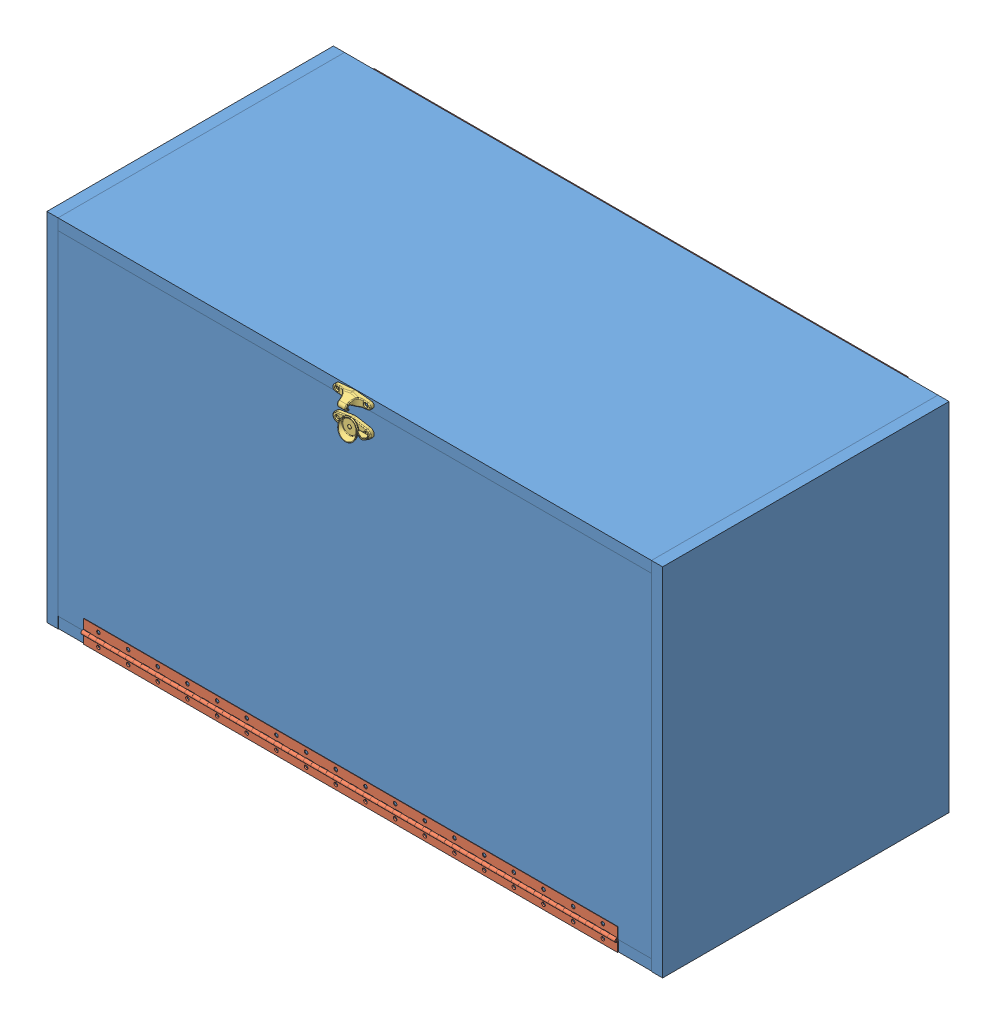
SolidWorks assembly box_assem, configuration Default. Lengths in mm.
Overall size (1054.1 609.6 520.48).
4 component instances, 3 part files, 7 mates.
Components (placement in the parent):
- boxV2-1: boxV2 [Default] at (-78.8871 -590.55 648.0409) size (1054.1 609.6 490.5)
- box-hinge-3: box-hinge [1569A395] at (-85.2005 -590.55 895.6274) x (0 1 0) z (1 0 0) size (38.1 6.22 914.4)
- box-hinge-4: box-hinge [1569A395] at (-80.6832 -19.05 399.6811) x (0 -1 0) z (1 0 0) size (38.1 6.22 914.4)
- latch-1: latch [Default] at (-78.2079 -31.6517 893.2891) x (-1 0 0) z (0 1 0) size (65.09 23.76 69.87)
Mates (geometry in assembly coordinates):
- Coincident6: coincident aligned: plane of boxV2-1 through (-78.8871 0 648.0409) normal (0 1 0)
- Coincident7: coincident anti-aligned: plane of boxV2-1 through (-586.8871 -609.6 892.5159) normal (0 0 1); plane of box-hinge-3 through (-529.7005 -609.6 892.5159) normal (0 0 -1)
- Coincident8: coincident anti-aligned: line of boxV2-1 through (-586.8871 -609.6 892.5159) axis (1 0 0); line of box-hinge-3 through (371.9995 -609.6 892.5159) axis (-1 0 0)
- Coincident9: coincident anti-aligned: plane of boxV2-1 through (-586.8871 -19.05 402.7926) normal (0 0 -1); plane of box-hinge-4 through (376.5168 -38.1 402.7926) normal (0 0 1)
- Coincident10: coincident aligned: line of boxV2-1 through (429.1129 0 402.7926) axis (-1 0 0); line of box-hinge-4 through (376.5168 0 402.7926) axis (-1 0 0)
- Coincident11: coincident anti-aligned: plane of boxV2-1 through (-78.8871 -590.55 893.2891) normal (0 0 1); plane of latch-1 through (-53.3944 -50.7017 893.2891) normal (0 0 -1)
- Parallel3: parallel anti-aligned: line of boxV2-1 through (-586.8871 -19.05 893.2891) axis (1 0 0); line of latch-1 through (-72.2389 -8.7722 914.1122) axis (-1 0 0)
